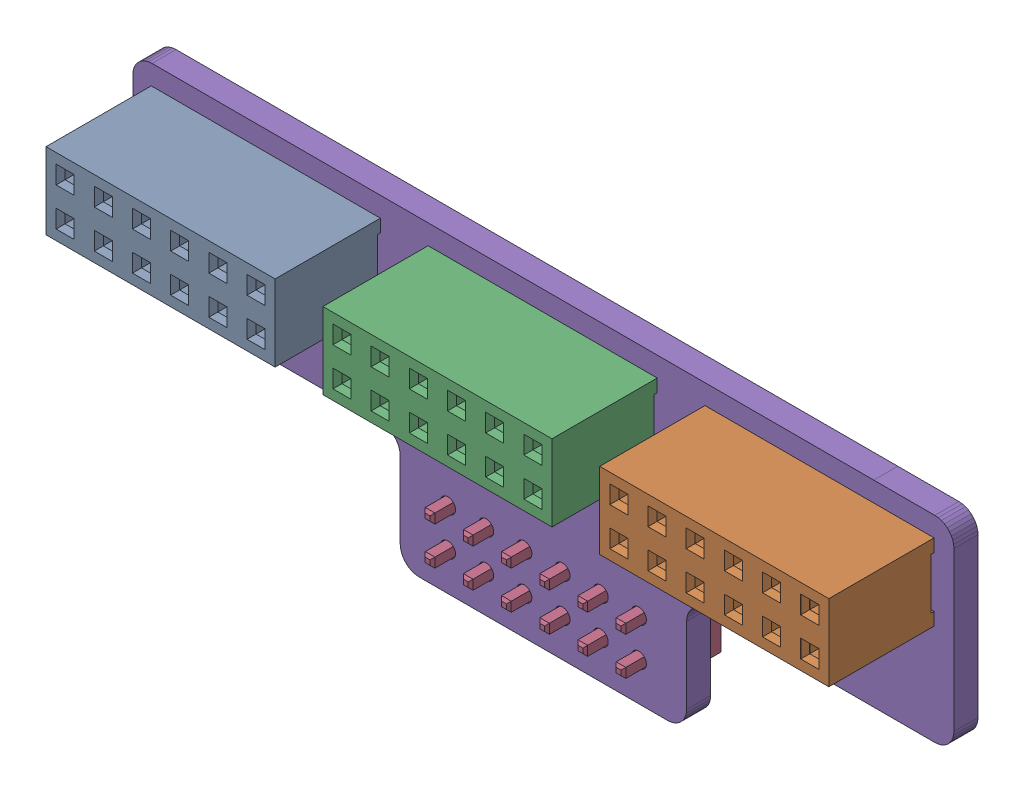
SolidWorks assembly PCB_V2(2), configuration Défaut. Lengths in mm.
Overall size (54.61 20.7 17.24).
15 component instances, 4 part files, 0 mates.
Components (placement in the parent):
- PinSocket_2x06_P2.54mm_Vertical_1-1: PinSocket_2x06_P2.54mm_Vertical_1 [Défaut] at (175.26 -77.724 1.65) x (0 1 0) z (0 0 1) size (5.08 15.24 10.1)
  - SOLID-1: SOLID [Défaut] at origin size (5.08 15.24 10.1)
- TerminalBlock_Phoenix_MKDS-1,5-2-5.08_1x02_P5.08mm_Horizontal_1.step-1: TerminalBlock_Phoenix_MKDS-1,5-2-5.08_1x02_P5.08mm_Horizontal_1.step [Défaut] at (178.435 -37.465 1.65) x (-1 0 0) z (0 0 1) (suppressed, hidden)
- PinSocket_2x06_P2.54mm_Vertical_1-2: PinSocket_2x06_P2.54mm_Vertical_1 [Défaut] at (212.09 -77.724 1.65) x (0 1 0) z (0 0 1) size (5.08 15.24 10.1)
  - SOLID-1: SOLID [Défaut] at origin size (5.08 15.24 10.1)
- PinHeader_1x04_P2.54mm_Vertical_1.step-1: PinHeader_1x04_P2.54mm_Vertical_1.step [Défaut] at (196.215 -70.485 1.65) x (0 1 0) z (0 0 1) (suppressed, hidden)
- PinHeader_1x10_P2.54mm_Vertical_1.step-1: PinHeader_1x10_P2.54mm_Vertical_1.step [Défaut] at (188.468 -35.56 1.65) x (0 1 0) z (0 0 1) (suppressed, hidden)
- PinHeader_1x04_P2.54mm_Vertical_1.step-4: PinHeader_1x04_P2.54mm_Vertical_1.step [Défaut] at (182.245 -70.485 1.65) x (0 1 0) z (0 0 1) (suppressed, hidden)
- PinSocket_2x06_P2.54mm_Vertical_1-3: PinSocket_2x06_P2.54mm_Vertical_1 [Défaut] at (193.675 -77.724 1.65) x (0 1 0) z (0 0 1) size (5.08 15.24 10.1)
  - SOLID-1: SOLID [Défaut] at origin size (5.08 15.24 10.1)
- PinHeader_1x04_P2.54mm_Vertical_1.step-3: PinHeader_1x04_P2.54mm_Vertical_1.step [Défaut] at (210.185 -70.485 1.65) x (0 1 0) z (0 0 1) (suppressed, hidden)
- PinHeader_2x06_P2.54mm_Vertical_1-1: PinHeader_2x06_P2.54mm_Vertical_1 [Défaut] at (193.675 -90.805 -0.05) x (0 -1 0) z (0 0 -1) size (5.08 15.24 11.54)
  - SOLID-3_1-1: SOLID-3_1 [Défaut] at origin size (5.08 15.24 11.54)
- PCB_V2 PCB1_1-1: PCB_V2 PCB1_1 [Défaut] at origin size (54.61 20.7 1.6)
- PCB_V2 PCB2_1-1: PCB_V2 PCB2_1 [Défaut] at origin size (62.23 42.55 1.6) (suppressed, hidden)
